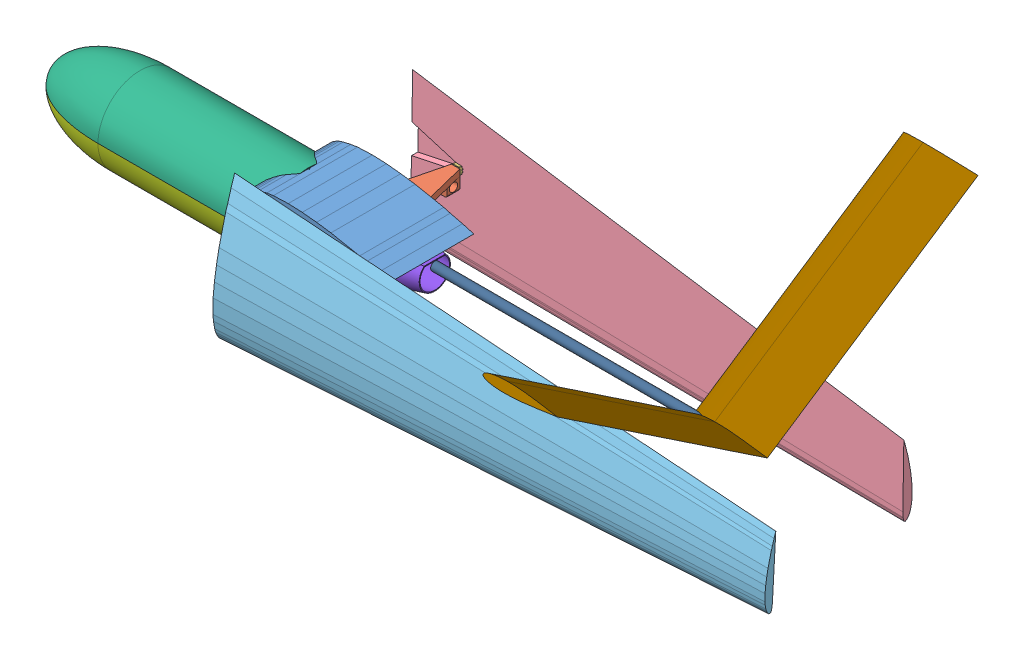
SolidWorks assembly kanat stm montaj, configuration Varsayılan. Lengths in mm.
Overall size (1839.43 577.72 1010.33).
13 component instances, 10 part files, 30 mates.
Components (placement in the parent):
- Kanat stm 1-1: Kanat stm 1 [Varsayılan] at (5.278 16.5377 243.2741) size (343.27 42.18 200)
- kanat stm 2-1: kanat stm 2 [Varsayılan] at (33.641 -2.5521 193.2741) x (-1 0 0) z (0 1 0) size (70 115 45)
- kanat stm 3-1: kanat stm 3 [Varsayılan] at (33.641 4.9479 543.2741) x (-0.053023 -0.998593 0) z (0 0 1) size (20 15 35)
- kanat stm 3-2: kanat stm 3 [Varsayılan] at (33.641 4.9479 143.2741) x (-0.016098 -0.99987 0) z (0 0 -1) size (20 15 35)
- kanat stm 2-2: kanat stm 2 [Varsayılan] at (33.641 -2.5521 493.2741) x (1 0 0) z (0 1 0) size (70 115 45)
- sağ kanat stm-1: sağ kanat stm [Varsayılan] at (-114.2191 379.5002 87.0666) x (0.016098 0.99987 0) z (-0.999451 0.016092 -0.028975) size (343.27 42.18 1200)
- yeni kanat sol-1: yeni kanat sol [Varsayılan] at (-57.9312 382.4349 604.655) x (0.053023 0.998593 0) z (0.994974 -0.05283 -0.085062) size (343.27 42.18 1200.01)
- Yeni göde skin 1 üst-1: Yeni göde skin 1 üst [Varsayılan] at (-400.4041 -64.6384 343.2741) x (1 0 0) z (0 1 0) size (602.96 200 100)
- Yeni göde skin 1-1: Yeni göde skin 1 [Varsayılan] at (-400.4041 -64.6384 343.2741) x (1 0 0) z (0 -1 0) size (549.96 200 100)
- yeni gövde skin 2-1: yeni gövde skin 2 [Varsayılan] at (-165.7366 -66.5521 343.2741) x (0 0 1) z (-1 0 0) size (218.07 177.05 350.02)
- kuyruk 1-1: kuyruk 1 [Varsayılan] at (774.2634 -16.7859 343.2741) x (1 0 0) z (0 0.551965 -0.833868) size (176.57 20.52 610.03)
- kuyruk 1-2: kuyruk 1 [Varsayılan] at (774.2634 -16.7859 343.2741) x (1 0 0) z (0 0.556176 0.831065) size (176.57 20.52 610.03)
- Kuyruk sbt 1-1: Kuyruk sbt 1 [Varsayılan] at (184.2634 -16.7859 343.2741) x (0 0.551555 0.834139) z (1 0 0) size (20 20 700)
Mates (geometry in assembly coordinates):
- Çakışık8: coincident anti-aligned: plane of Kanat stm 1-1 through (5.278 16.5377 443.2741) normal (0 0 1); plane of kanat stm 2-2 through (-1.359 12.4479 443.2741) normal (0 0 -1)
- Çakışık9: coincident: point of Kanat stm 1-1; point of kanat stm 2-2
- Çakışık12: coincident: point of Kanat stm 1-1; point of kanat stm 2-2
- Eş Merkezli1: concentric anti-aligned: circle of kanat stm 3-1; circle of kanat stm 2-2
- Çakışık13: coincident anti-aligned: plane of kanat stm 3-1 through (33.641 4.9479 543.2741) normal (0 0 -1); plane of kanat stm 2-2 through (23.641 12.4479 543.2741) normal (0 0 1)
- Çakışık14: coincident anti-aligned: plane of Kanat stm 1-1 through (5.278 16.5377 243.2741) normal (0 0 -1); plane of kanat stm 2-1 through (68.641 12.4479 243.2741) normal (0 0 1)
- Çakışık17: coincident: point of Kanat stm 1-1; point of kanat stm 2-1
- Çakışık18: coincident: point of Kanat stm 1-1; point of kanat stm 2-1
- Eş Merkezli2: concentric anti-aligned: circle of kanat stm 2-1; circle of kanat stm 3-2
- Çakışık19: coincident anti-aligned: plane of kanat stm 2-1 through (43.641 12.4479 143.2741) normal (0 0 -1); plane of kanat stm 3-2 through (33.641 4.9479 143.2741) normal (0 0 1)
- Eş Merkezli3: concentric aligned: cylinder of kanat stm 3-2 through (34.3654 49.9421 128.2741) axis (-0.016098 -0.99987 0) radius 5; cylinder of sağ kanat stm-1 through (33.9629 24.9453 128.2741) axis (-0.016098 -0.99987 0) radius 5
- Çakışık22: coincident: plane of assembly through (0 0 0) normal (0 1 0); plane of Kanat stm 1-1 through (176.915 -4.5521 443.2741) normal (0 -1 0); plane of assembly
- Çakışık23: coincident anti-aligned: plane of kanat stm 3-2 through (25.1837 6.5843 128.2741) normal (-0.016098 -0.99987 0); plane of sağ kanat stm-1 through (39.6156 6.3519 91.1412) normal (0.016098 0.99987 0)
- Eş Merkezli4: concentric aligned: line of kanat stm 3-1 through (36.027 49.8846 558.2741) axis (-0.053023 -0.998593 0); axis of yeni kanat sol-1 through (34.7002 24.897 558.2741) axis (-0.053023 -0.998593 0)
- Çakışık24: coincident anti-aligned: plane of kanat stm 3-1 through (42.1911 5.996 558.2741) normal (-0.053023 -0.998593 0); plane of yeni kanat sol-1 through (42.4821 5.9806 594.8129) normal (0.053023 0.998593 0)
- Eş Merkezli5: concentric: circle of Yeni göde skin 1-1; circle of yeni gövde skin 2-1
- Çakışık25: coincident: plane of Yeni göde skin 1-1 through (-165.7366 -64.6384 341.2741) normal (1 0 0); plane of yeni gövde skin 2-1 through (-165.7366 -66.5521 343.2741) normal (-1 0 0)
- Paralel1: parallel: plane of Yeni göde skin 1-1 through (-515.7366 -64.6384 343.2741) normal (0 1 0); plane of yeni gövde skin 2-1 through (-165.7366 -4.5521 343.2741) normal (0 1 0)
- Çakışık26: coincident: plane of Yeni göde skin 1 üst-1 through (-515.7366 -64.6384 343.2741) normal (0 -1 0); plane of Yeni göde skin 1-1 through (-515.7366 -64.6384 343.2741) normal (0 1 0)
- Çakışık27: coincident: plane of Yeni göde skin 1 üst-1 through (-165.7366 -64.6384 345.2741) normal (1 0 0); plane of yeni gövde skin 2-1 through (-165.7366 -66.5521 343.2741) normal (-1 0 0)
- Eş Merkezli6: concentric: circle of Yeni göde skin 1 üst-1; circle of Yeni göde skin 1-1
- Çakışık31: coincident: plane of Kanat stm 1-1 through (5.278 16.5377 343.2741) normal (0 0 1); plane of Yeni göde skin 1 üst-1 through (-112.7366 -64.6384 343.2741) normal (0 0 -1)
- Çakışık32: coincident: line of Kanat stm 1-1 through (-166.359 6.6197 443.2741) axis (0 0 -1); line of Yeni göde skin 1 üst-1 through (-166.359 6.6197 273.1151) axis (0 0 1)
- Çakışık33: coincident: plane of Kanat stm 1-1 through (176.915 -4.5521 443.2741) normal (0 -1 0); plane of yeni gövde skin 2-1 through (-165.7366 -4.5521 343.2741) normal (0 1 0)
- Çakışık36: coincident aligned: plane of kuyruk 1-1 through (834.2634 -16.7859 343.2741) normal (-1 0 0); plane of kuyruk 1-2 through (834.2634 -16.7859 343.2741) normal (-1 0 0)
- Eş Merkezli8: concentric aligned: circle of kuyruk 1-1; circle of kuyruk 1-2
- Çakışık39: coincident aligned: circle of kuyruk 1-1; plane of kuyruk 1-2 through (884.2634 -16.7859 343.2741) normal (1 0 0)
- Eş Merkezli11: concentric aligned: circle of kuyruk 1-1; circle of Kuyruk sbt 1-1
- Çakışık60: coincident aligned: circle of kuyruk 1-1; plane of Kuyruk sbt 1-1 through (884.2634 -16.7859 343.2741) normal (1 0 0)
- Çakışık61: coincident anti-aligned: plane of yeni gövde skin 2-1 through (184.2634 -31.5521 343.2741) normal (1 0 0); plane of Kuyruk sbt 1-1 through (184.2634 -16.7859 343.2741) normal (-1 0 0)
